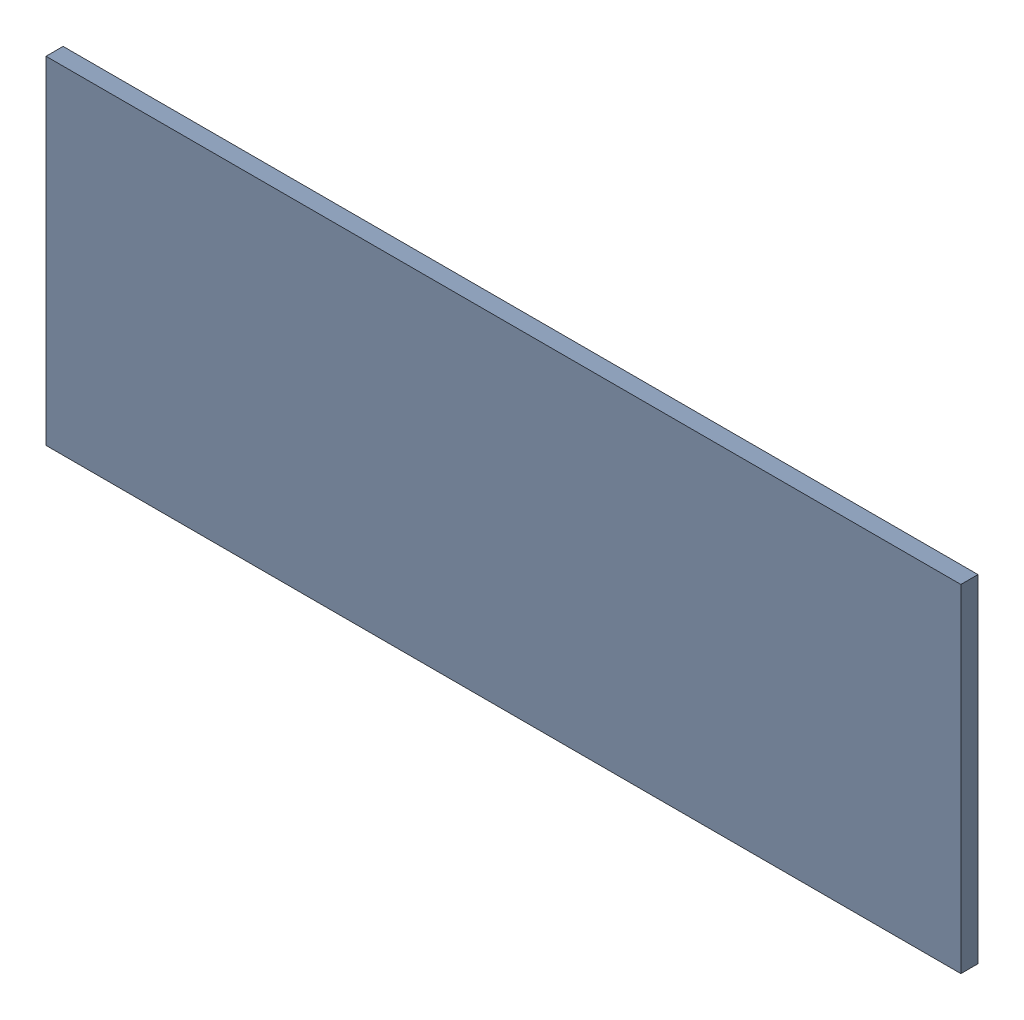
SolidWorks assembly Pad RAK4600-34(29.2mm,27.5mm) on Top Layer, configuration Predeterminado. Lengths in mm.
Overall size (1.9 0.7 0.04).
2 component instances, 1 part files, 0 mates.
Components (placement in the parent):
- Pad RAK4600-34(29.2mm,27.5mm) on Top Layer-1-1: Pad RAK4600-34(29.2mm,27.5mm) on Top Layer-1 [Predeterminado] at (-68.317 -44.187 -0.0457) size (1.9 0.7 0.04)
  - Pad RAK4600-34(29.2mm,27.5mm) on Top Layer-Part-1-1: Pad RAK4600-34(29.2mm,27.5mm) on Top Layer-Part-1 [Predeterminado] at origin size (1.9 0.7 0.04)
